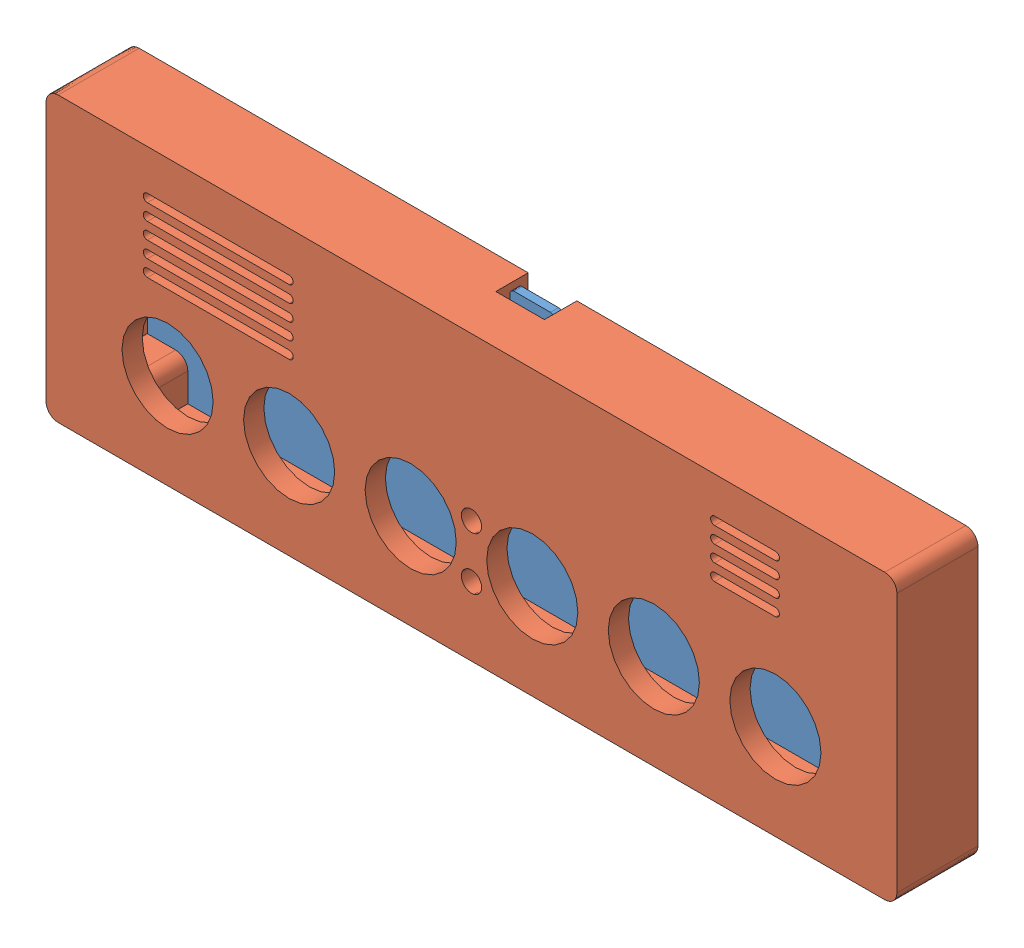
SolidWorks assembly 装配体1, configuration 默认. Lengths in mm.
Overall size (210 70 20).
2 component instances, 2 part files, 4 mates.
Components (placement in the parent):
- 电路样板-1: 电路样板 [默认] at origin size (190 64.3 2)
- 一体化框架-木-1: 一体化框架-木 [默认] at (-10 5 -3) size (210 70 20)
Mates (geometry in assembly coordinates):
- 平行1: parallel: plane of 电路样板-1 through (0 0 2) normal (0 0 1); plane of 一体化框架-木-1 through (153 -6.5 2) normal (0 0 -1)
- 重合2: coincident: plane of 电路样板-1 through (-30 -13.5 2) normal (0 -1 0); plane of 一体化框架-木-1 through (-30 -13.5 12) normal (0 1 0)
- 重合3: coincident: plane of 电路样板-1 through (-30 46.5 2) normal (-1 0 0); plane of 一体化框架-木-1 through (-30 46.5 12) normal (1 0 0)
- 重合4: coincident: plane of 电路样板-1 through (0 0 2) normal (0 0 1); plane of 一体化框架-木-1 through (-23 -6.5 2) normal (0 0 -1)
